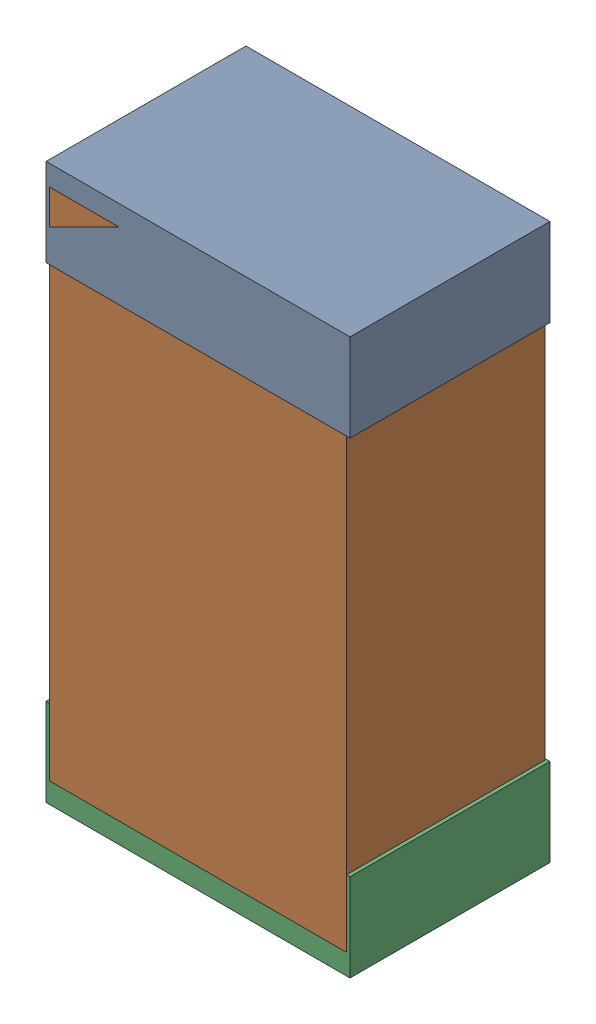
SolidWorks assembly R11Kanaloa_v2.0.0_Power, configuration Default. Lengths in mm.
Overall size (1.3 2.38 0.85).
6 component instances, 2 part files, 0 mates.
Components (placement in the parent):
- 330415056-1: 330415056 [Default] at (99.25 65.675 -1.9574) size (1.3 0.38 0.85)
  - Extruded_2-1: Extruded_2 [Default] at origin size (1.3 0.38 0.85)
- 352877008-1: 352877008 [Default] at (99.25 64.675 -1.9524) size (1.27 2.2 0.85)
  - Extruded_3-1: Extruded_3 [Default] at origin size (1.27 2.2 0.85)
- 330415056-2: 330415056 [Default] at (99.25 63.675 -1.9574) size (1.3 0.38 0.85)
  - Extruded_2-1: Extruded_2 [Default] at origin size (1.3 0.38 0.85)
